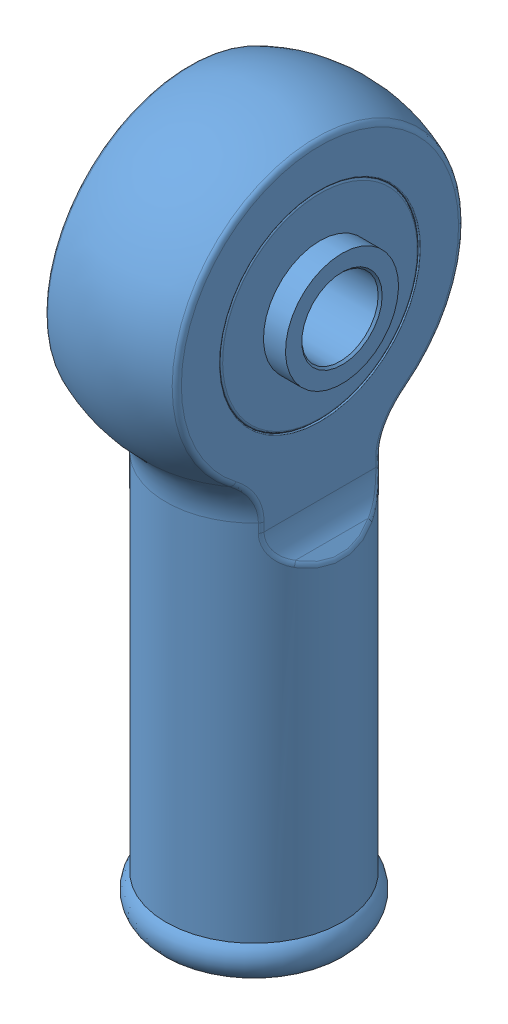
SolidWorks assembly REPB3N2 Assy, configuration 1_START HERE. Lengths in mm.
Overall size (11.97 44.84 19.84).
2 component instances, 1 part files, 1 mates.
Components (placement in the parent):
- REPB3N2-1: REPB3N2 [Housing] at origin size (11.97 44.84 19.84)
- REPB3N2-2: REPB3N2 [Ball] at origin size (11.97 44.84 19.84)
Mates (geometry in assembly coordinates):
- Concentric1: concentric: sphere of REPB3N2-1; sphere of REPB3N2-2
